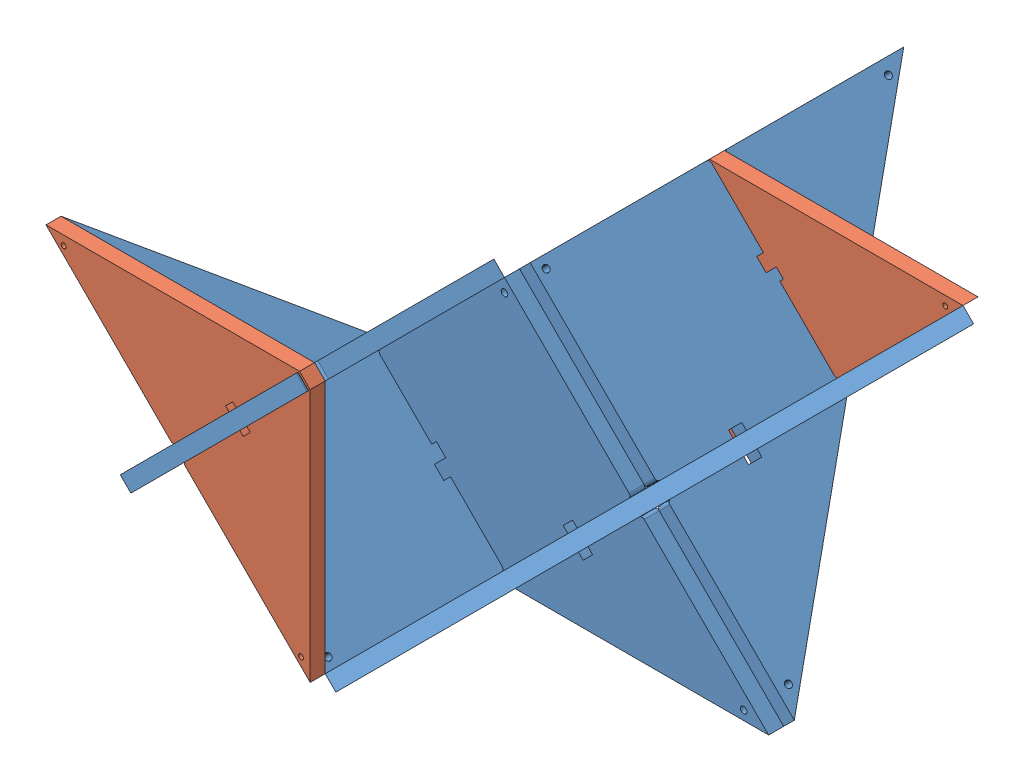
SolidWorks assembly prew3, configuration Default. Lengths in mm.
Overall size (661.99 801.89 918.1).
7 component instances, 2 part files, 18 mates.
Components (placement in the parent):
- aglebig-7: aglebig [angle_small] at (-207.0166 770.7683 -371.4805) x (0.707107 -0.707107 0) z (0.707107 0.707107 0) size (450 18.1 450)
- aglebig-8: aglebig [angle_small] at (-169.113 522.0777 -574.1331) x (0 0 1) z (-0.707107 -0.707107 0) size (450 18.1 450)
- aglebig-9: aglebig [angle_small] at (-183.3635 794.4214 -423.031) x (0.707107 -0.707107 0) z (0 0 1) size (450 18.1 450)
- angle_small-5: angle_small [Default] at (-46.3582 717.7361 -605.5305) x (-0.707107 -0.707107 0) z (0.707107 -0.707107 0) size (450 18.1 215.95)
- aglebig-11: aglebig [angle_small] at (-242.0165 522.0777 -186.9278) x (0 0 -1) z (0.707107 -0.707107 0) size (450 18.1 450)
- aglebig-14: aglebig [angle_small] at (-227.766 794.4214 -338.0299) x (-0.707107 -0.707107 0) z (0 0 -1) size (450 18.1 450)
- angle_small-6: angle_small [Default] at (-364.7713 717.7361 -155.5305) x (0.707107 -0.707107 0) z (-0.707107 -0.707107 0) size (450 18.1 215.95)
Mates (geometry in assembly coordinates):
- Coincident28: coincident anti-aligned: plane of aglebig-7 through (-259.7133 718.0715 -389.5805) normal (0.707107 0.707107 0); plane of aglebig-8 through (-129.2149 587.5731 -574.1331) normal (-0.707107 -0.707107 0)
- Coincident29: coincident anti-aligned: line of aglebig-7 through (-105.1026 586.0882 -371.4805) axis (0.707107 0.707107 0); line of aglebig-8 through (-127.73 563.4608 -371.4805) axis (-0.707107 -0.707107 0)
- Coincident30: coincident anti-aligned: plane of aglebig-8 through (-181.9116 534.8764 -497.5555) normal (0 0 -1); plane of aglebig-9 through (-170.5649 807.22 -497.5555) normal (0 0 1)
- Perpendicular4: perpendicular: plane of aglebig-8 through (-181.9116 534.8764 -574.1331) normal (-0.707107 0.707107 0); plane of aglebig-9 through (-183.3635 794.4214 -423.031) normal (-0.707107 -0.707107 0)
- Coincident32: coincident anti-aligned: line of aglebig-8 through (-52.8651 663.923 -513.5555) axis (0 0 -1); line of aglebig-9 through (-52.8651 663.923 -481.5555) axis (0 0 1)
- Coincident33: coincident anti-aligned: plane of aglebig-9 through (-116.4163 753.0714 -423.031) normal (-0.707107 0.707107 0); plane of angle_small-5 through (-129.2149 740.2728 -623.6305) normal (0.707107 -0.707107 0)
- Coincident34: coincident aligned: line of aglebig-9 through (-127.73 764.3852 -623.6305) axis (-0.707107 0.707107 0); line of angle_small-5 through (-42.1877 678.8429 -623.6305) axis (-0.707107 0.707107 0)
- Coincident44: coincident anti-aligned: plane of aglebig-7 through (-152.868 716.6197 -389.5805) normal (-0.707107 0.707107 0); plane of aglebig-11 through (-281.9146 587.5731 -186.9278) normal (0.707107 -0.707107 0)
- Coincident46: coincident anti-aligned: line of aglebig-7 through (-293.2283 598.8868 -371.4805) axis (-0.707107 0.707107 0); line of aglebig-11 through (-270.6009 576.2594 -371.4805) axis (0.707107 -0.707107 0)
- Parallel12: parallel aligned: line of aglebig-11 through (-376.72 682.3784 -263.5055) axis (0.707107 -0.707107 0); line of aglebig-14 through (-218.3634 829.4213 -371.4805) axis (0.707107 -0.707107 0)
- Coincident59: coincident anti-aligned: plane of aglebig-11 through (-229.2179 534.8764 -263.5055) normal (0 0 1); plane of aglebig-14 through (-240.5647 807.22 -263.5055) normal (0 0 -1)
- Coincident60: coincident anti-aligned: line of aglebig-11 through (-358.2645 663.923 -247.5055) axis (0 0 1); line of aglebig-14 through (-358.2645 663.923 -279.5055) axis (0 0 -1)
- Parallel13: parallel anti-aligned: line of aglebig-11 through (-373.8915 679.55 -155.5305) axis (-0.707107 0.707107 0); line of angle_small-6 through (-523.7628 829.4213 -137.4305) axis (0.707107 -0.707107 0)
- Parallel14: parallel aligned: line of aglebig-14 through (-283.3995 764.3852 -155.5305) axis (0.707107 0.707107 0); line of angle_small-6 through (-368.9418 678.8429 -155.5305) axis (0.707107 0.707107 0)
- Coincident63: coincident anti-aligned: plane of aglebig-14 through (-294.7132 753.0714 -338.0299) normal (0.707107 0.707107 0); plane of angle_small-6 through (-281.9146 740.2728 -137.4305) normal (-0.707107 -0.707107 0)
- Coincident64: coincident: line of aglebig-14 through (-283.3995 764.3852 -155.5305) axis (0.707107 0.707107 0); line of angle_small-6 through (-290.3999 731.7875 -155.5305) axis (-0.707107 -0.707107 0)
- Coincident66: coincident: plane of aglebig-14 through (-240.5647 807.22 -338.0299) normal (-0.707107 0.707107 0); line of angle_small-6 through (-368.9418 678.8429 -137.4305) axis (0.707107 0.707107 0)
- Coincident67: coincident anti-aligned: line of aglebig-14 through (-218.3634 829.4213 -133.4305) axis (0 0 1); line of angle_small-6 through (-218.3634 829.4213 -137.4305) axis (0 0 -1)
